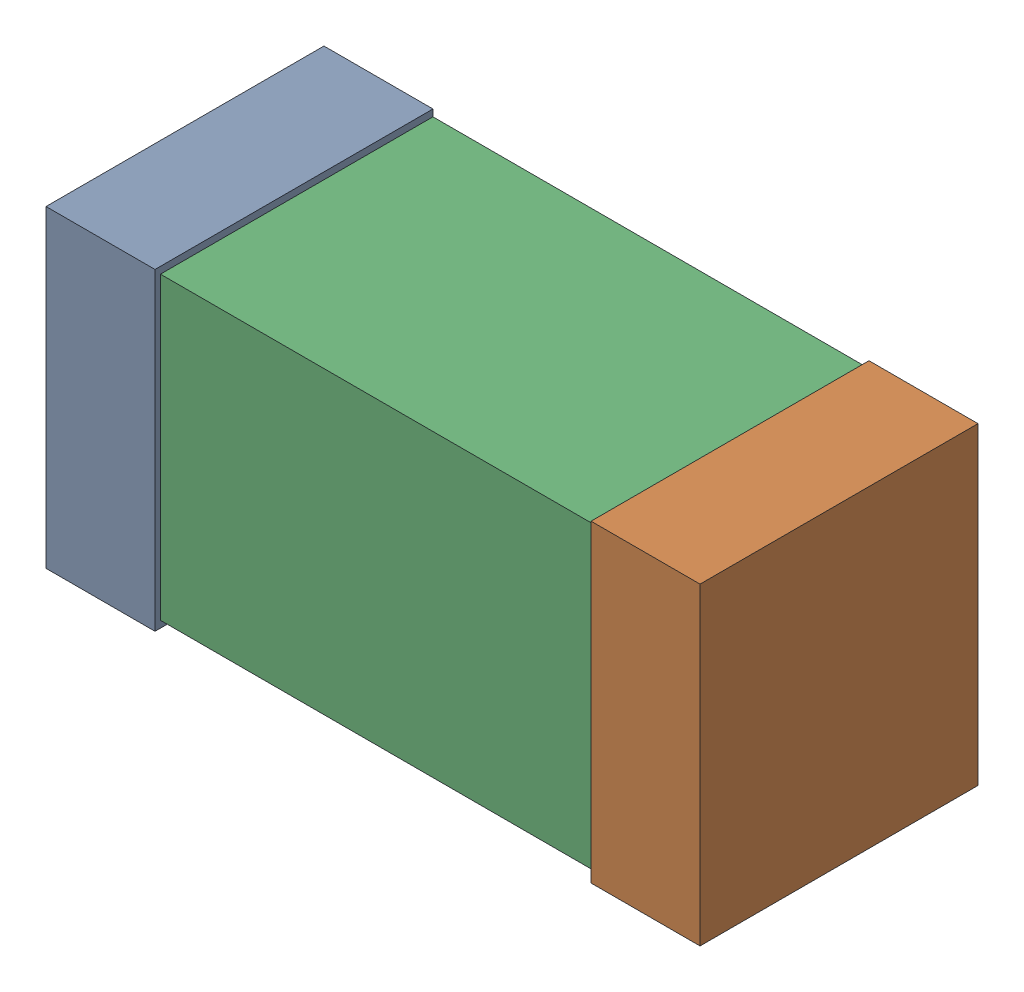
SolidWorks assembly .1uFKanaloa_v2.0.0_Power, configuration Default. Lengths in mm.
Overall size (1.2 0.58 0.51).
6 component instances, 2 part files, 0 mates.
Components (placement in the parent):
- 378153536-1: 378153536 [Default] at (142.8968 95.1464 0) size (0.2 0.58 0.51)
  - Extruded_19-1: Extruded_19 [Default] at origin size (0.2 0.58 0.51)
- 378153536-2: 378153536 [Default] at (143.8968 95.1464 0) size (0.2 0.58 0.51)
  - Extruded_19-1: Extruded_19 [Default] at origin size (0.2 0.58 0.51)
- 378153664-1: 378153664 [Default] at (143.3968 95.1464 0) size (1.15 0.55 0.5)
  - Extruded_20-1: Extruded_20 [Default] at origin size (1.15 0.55 0.5)
